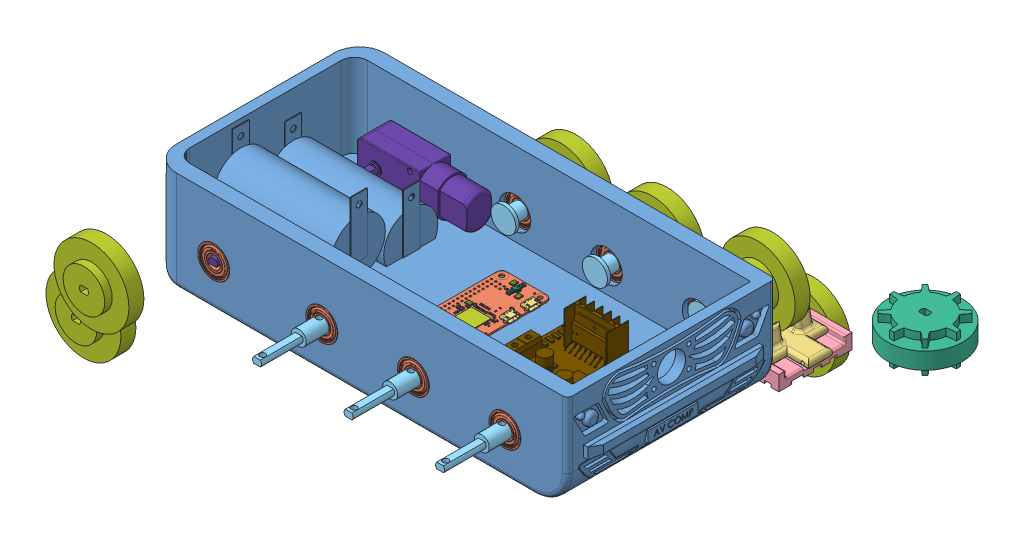
SolidWorks assembly AV_Comp_Mech_1_3_4_TotalAssembly2, configuration Default. Lengths in mm.
Overall size (366.9 156.49 292.26).
131 component instances, 26 part files, 45 mates.
Components (placement in the parent):
- AV_Comp_Mech_1_3_2_4_ChassisV2_Bot-1: AV_Comp_Mech_1_3_2_4_ChassisV2_Bot [Default] at (-27.4355 -20.1708 15.0222) size (256 60 125)
- AV_Comp_Mech_1_3_1_2_Pi_Zero-1: AV_Comp_Mech_1_3_1_2_Pi_Zero [Default] at (-36.7711 -30.2674 -38.0496) x (0 0 -1) z (1 0 0) size (65 4.45 31.23)
  - Raspberry_pizero_PCB-1: Raspberry_pizero_PCB [Default] at (-51.2564 20.0966 13.0542) size (65 1 30)
  - Micro USB_input_female (short)-SMT-1: Micro USB_input_female (short)-SMT [Default] at (-42.3564 22.3216 26.5042) size (7.98 2.94 5.43)
  - Micro USB_input_female (short)-SMT-2: Micro USB_input_female (short)-SMT [Default] at (-29.7564 22.3216 26.5042) size (7.98 2.94 5.43)
  - 0204 - Capacitor-1: 0204 - Capacitor [Default] at (-62.4121 21.3466 11.2398) size (1 0.5 0.6)
  - 0204 - Capacitor-2: 0204 - Capacitor [Default] at (-62.4121 21.3466 12.2528) size (1 0.5 0.6)
  - 0204 - Capacitor-3: 0204 - Capacitor [Default] at (-61.8122 21.3466 13.3136) size (1 0.5 0.6)
  - 0204 - Capacitor-4: 0204 - Capacitor [Default] at (-61.8122 21.3466 14.2646) size (1 0.5 0.6)
  - 0204 - Capacitor-5: 0204 - Capacitor [Default] at (-61.8122 21.3466 15.241) size (1 0.5 0.6)
  - 0204 - Capacitor-6: 0204 - Capacitor [Default] at (-61.8122 21.3466 16.2144) size (1 0.5 0.6)
  - 0204 - Capacitor-7: 0204 - Capacitor [Default] at (-61.8122 21.3466 17.2416) size (1 0.5 0.6)
  - 0204 - Capacitor-8: 0204 - Capacitor [Default] at (-62.5919 21.3466 20.9695) size (1 0.5 0.6)
  - 0204 - Capacitor-9: 0204 - Capacitor [Default] at (-62.5919 21.3466 21.919) size (1 0.5 0.6)
  - 0204 - Capacitor-10: 0204 - Capacitor [Default] at (-60.4584 21.3466 22.3712) x (0 0 1) z (-1 0 0) size (1 0.5 0.6)
  - 0204 - Capacitor-11: 0204 - Capacitor [Default] at (-60.0807 21.3466 22.3712) x (0 0 -1) z (1 0 0) size (1 0.5 0.6)
  - 0204 - Capacitor-12: 0204 - Capacitor [Default] at (-59.0466 21.3466 22.3712) x (0 0 -1) z (1 0 0) size (1 0.5 0.6)
  - 0204 - Capacitor-13: 0204 - Capacitor [Default] at (-52.6496 21.3466 22.316) x (0 0 1) z (-1 0 0) size (1 0.5 0.6)
  - 0204 - Capacitor-14: 0204 - Capacitor [Default] at (-52.25 21.3466 22.316) x (0 0 -1) z (1 0 0) size (1 0.5 0.6)
  - 0204 - Capacitor-15: 0204 - Capacitor [Default] at (-51.2398 21.3466 22.316) x (0 0 -1) z (1 0 0) size (1 0.5 0.6)
  - 0204 - Capacitor-16: 0204 - Capacitor [Default] at (-49.1841 21.3466 22.316) x (0 0 -1) z (1 0 0) size (1 0.5 0.6)
  - 0204 - Capacitor-17: 0204 - Capacitor [Default] at (-48.1448 21.3466 22.316) x (0 0 -1) z (1 0 0) size (1 0.5 0.6)
  - 0204 - Capacitor-18: 0204 - Capacitor [Default] at (-46.475 21.3466 21.113) size (1 0.5 0.6)
  - 0204 - Capacitor-19: 0204 - Capacitor [Default] at (-45.7322 21.3466 20.0663) size (1 0.5 0.6)
  - 0204 - Capacitor-20: 0204 - Capacitor [Default] at (-45.7322 21.3466 19.0675) size (1 0.5 0.6)
  - 0204 - Capacitor-21: 0204 - Capacitor [Default] at (-45.7322 21.3466 18.1249) size (1 0.5 0.6)
  - 0204 - Capacitor-22: 0204 - Capacitor [Default] at (-45.7322 21.3466 17.1095) size (1 0.5 0.6)
  - 0204 - Capacitor-23: 0204 - Capacitor [Default] at (-46.3457 21.3466 16.1412) size (1 0.5 0.6)
  - 0204 - Capacitor-24: 0204 - Capacitor [Default] at (-46.3457 21.3466 15.1229) size (1 0.5 0.6)
  - 0204 - Capacitor-25: 0204 - Capacitor [Default] at (-46.3457 21.3466 14.0197) size (1 0.5 0.6)
  - 0204 - Capacitor-26: 0204 - Capacitor [Default] at (-46.3457 21.3466 12.9589) size (1 0.5 0.6)
  - 0204 - Capacitor-27: 0204 - Capacitor [Default] at (-43.6156 21.3466 13.1418) size (1 0.5 0.6)
  - 0204 - Capacitor-28: 0204 - Capacitor [Default] at (-43.6156 21.3466 10.1424) size (1 0.5 0.6)
  - 0204 - Capacitor-29: 0204 - Capacitor [Default] at (-48.9117 21.3466 7.6917) size (1 0.5 0.6)
  - 0204 - Capacitor-30: 0204 - Capacitor [Default] at (-55.4926 21.3466 7.2526) x (0 0 -1) z (1 0 0) size (1 0.5 0.6)
  - 0204 - Capacitor-31: 0204 - Capacitor [Default] at (-53.7932 21.3466 7.2526) x (0 0 1) z (-1 0 0) size (1 0.5 0.6)
  - 0204 - Capacitor-32: 0204 - Capacitor [Default] at (-59.8477 21.3466 7.2526) x (0 0 1) z (-1 0 0) size (1 0.5 0.6)
  - 0204- Resistor-15: 0204- Resistor [Default] at (-43.6109 21.4522 15.4193) x (-1 0 0) z (0 -1 0) size (0.99 0.51 0.36)
  - 0204- Resistor-14: 0204- Resistor [Default] at (-43.6109 21.4522 14.4127) x (-1 0 0) z (0 -1 0) size (0.99 0.51 0.36)
  - 0204- Resistor-13: 0204- Resistor [Default] at (-43.6109 21.4522 12.4047) x (-1 0 0) z (0 -1 0) size (0.99 0.51 0.36)
  - 0204- Resistor-4: 0204- Resistor [Default] at (-42.6936 21.4522 18.4076) x (-1 0 0) z (0 -1 0) size (0.99 0.51 0.36)
  - 0204- Resistor-5: 0204- Resistor [Default] at (-39.831 21.4522 18.1462) x (0 0 1) z (0 -1 0) size (0.99 0.51 0.36)
  - 0204- Resistor-7: 0204- Resistor [Default] at (-61.8169 21.4522 19.8533) x (-1 0 0) z (0 -1 0) size (0.99 0.51 0.36)
  - 0204- Resistor-8: 0204- Resistor [Default] at (-61.8169 21.4522 18.5178) x (-1 0 0) z (0 -1 0) size (0.99 0.51 0.36)
  - 0204- Resistor-9: 0204- Resistor [Default] at (-79.148 21.4522 17.7279) x (-1 0 0) z (0 -1 0) size (0.99 0.51 0.36)
  - 0204- Resistor-10: 0204- Resistor [Default] at (-56.0985 21.4522 7.2479) x (0 0 -1) z (0 -1 0) size (0.99 0.51 0.36)
  - 0204- Resistor-11: 0204- Resistor [Default] at (-28.0827 21.4522 9.5819) x (-1 0 0) z (0 -1 0) size (0.99 0.51 0.36)
  - 0204- Resistor-12: 0204- Resistor [Default] at (-21.8613 21.4522 20.9026) x (-1 0 0) z (0 -1 0) size (0.99 0.51 0.36)
  - CAP-0306-1: CAP-0306 [Default] at (-45.8903 21.4966 8.7634) size (1.6 0.8 0.9)
  - CAP-0306-2: CAP-0306 [Default] at (-82.0031 21.4966 19.0464) x (0 0 1) z (-1 0 0) size (1.6 0.8 0.9)
  - Raspberry_pizero_BCM2835 with VC4-2: Raspberry_pizero_BCM2835 with VC4 [Default] at (-54.1608 21.5466 15.1238) x (1 0 0) z (0 0 -1) size (12 0.65 12)
  - Crystal 3.4x2.4mm-1: Crystal 3.4x2.4mm [Default] at (-65.3089 21.0966 19.2633) size (3.2 1 2.4)
  - 0204- Resistor-16: 0204- Resistor [Default] at (-68.4329 21.4522 5.4384) x (0 0 1) z (0 -1 0) size (0.99 0.51 0.36)
  - 0204- Resistor-17: 0204- Resistor [Default] at (-69.7255 21.4522 5.4384) x (0 0 1) z (0 -1 0) size (0.99 0.51 0.36)
  - 0204- Resistor-18: 0204- Resistor [Default] at (-65.0626 21.4522 16.5355) x (1 0 0) z (0 -1 0) size (0.99 0.51 0.36)
  - 32,768 Khz Crystal-1: 32,768 Khz Crystal [Default] at (-60.5154 21.1428 26.5473) x (0.999848 -0.017452 0) z (0 0 1) size (3.4 1.03 1.5)
  - 0805- Capacitor-1: 0805- Capacitor [Default] at (-51.9496 21.9966 5.2384) x (1 0 0) z (0 -1 0) size (2 1.25 0.9)
  - 0805- Capacitor-2: 0805- Capacitor [Default] at (-51.9496 21.9966 7.3589) x (1 0 0) z (0 -1 0) size (2 1.25 0.9)
  - 0805- Capacitor-3: 0805- Capacitor [Default] at (-37.009 21.9966 22.5384) x (0 0 -1) z (0 -1 0) size (2 1.25 0.9)
  - 0805- Capacitor-4: 0805- Capacitor [Default] at (-29.8247 21.9966 13.3538) x (0 0 1) z (0 -1 0) size (2 1.25 0.9)
  - 0805- Capacitor-5: 0805- Capacitor [Default] at (-27.9052 21.9966 13.3538) x (0 0 -1) z (0 -1 0) size (2 1.25 0.9)
  - 0805- Capacitor-6: 0805- Capacitor [Default] at (-22.8003 21.9966 13.3538) x (0 0 -1) z (0 -1 0) size (2 1.25 0.9)
  - 0805- Capacitor-7: 0805- Capacitor [Default] at (-20.9924 21.9966 13.3538) x (0 0 -1) z (0 -1 0) size (2 1.25 0.9)
  - 0204- Resistor-19: 0204- Resistor [Default] at (-48.8769 21.4522 23.8207) x (1 0 0) z (0 -1 0) size (0.99 0.51 0.36)
  - 0204- Resistor-20: 0204- Resistor [Default] at (-52.4165 21.4522 24.0419) x (1 0 0) z (0 -1 0) size (0.99 0.51 0.36)
  - 0204 - Capacitor-33: 0204 - Capacitor [Default] at (-47.1199 21.3466 23.926) x (0 0 1) z (-1 0 0) size (1 0.5 0.6)
  - 0204 - Capacitor Brown-34: 0204 - Capacitor Brown [Default] at (-57.5817 21.3466 26.803) size (1 0.5 0.6)
  - 0204 - Capacitor Brown-35: 0204 - Capacitor Brown [Default] at (-64.0312 21.3466 26.8794) size (1 0.5 0.6)
  - 0204 - Capacitor Brown-36: 0204 - Capacitor Brown [Default] at (-46.3457 21.3466 12.214) size (1 0.5 0.6)
  - 0204 - Capacitor Brown-37: 0204 - Capacitor Brown [Default] at (-46.3457 21.3466 11.0963) size (1 0.5 0.6)
  - 0204 - Capacitor Brown-38: 0204 - Capacitor Brown [Default] at (-46.3457 21.3466 10.1566) size (1 0.5 0.6)
  - 0204 - Capacitor Brown-39: 0204 - Capacitor Brown [Default] at (-43.6156 21.3466 11.1151) size (1 0.5 0.6)
  - 0204 - Capacitor Brown-40: 0204 - Capacitor Brown [Default] at (-28.0874 21.3466 10.3236) size (1 0.5 0.6)
  - 0204 - Capacitor Brown-41: 0204 - Capacitor Brown [Default] at (-80.6197 21.3466 20.6997) size (1 0.5 0.6)
  - 0204- Resistor-21: 0204- Resistor [Default] at (-78.9105 21.4522 21.1554) x (1 0 0) z (0 -1 0) size (0.99 0.51 0.36)
  - 6-Pin SOT-1: 6-Pin SOT [Default] at (-79.714 21.0966 19.2138) x (0 0 1) z (0 1 0) size (1.5 1.84 0.95)
  - micro sd molex-1: micro sd molex [Default] at (-74.7768 21.6766 -33.0961) x (0 0 1) z (0 1 0) size (11.95 11.4 1.45)
  - hdmi type C-1: hdmi type C [Default] at (-71.3564 22.9466 28.6542) size (12.9 4.05 7.7)
  - Voltage Regulator 3x3mm 12-Pin-1: Voltage Regulator 3x3mm 12-Pin [Default] at (-23.6842 21.0966 12.6105) x (1 0 0) z (0 1 0) size (3 4.1 1.2)
  - 1210 inductor-1: 1210 inductor [Default] at (-46.4963 21.0916 6.3909) x (0 0 1) z (0 1 0) size (3.26 2.86 0.75)
  - 1210 inductor-2: 1210 inductor [Default] at (-22.7405 21.0916 9.2394) x (1 0 0) z (0 1 0) size (3.26 2.86 0.75)
  - 1210 inductor-3: 1210 inductor [Default] at (-28.2854 21.0916 17.6682) x (1 0 0) z (0 1 0) size (3.26 2.86 0.75)
  - 0204 - Capacitor-34: 0204 - Capacitor [Default] at (-48.9117 21.3466 6.5273) size (1 0.5 0.6)
- AV_Comp_Mech_1_3_1_3_Motors-1: AV_Comp_Mech_1_3_1_3_Motors [Default] at (-114.9355 4.8292 -38.4778) x (0 1 0) z (0 0 1) size (22.6 65.53 37.6)
- AV_Comp_Mech_1_3_1_4_L298N_Motor_Driver-1: AV_Comp_Mech_1_3_1_4_L298N_Motor_Driver [Default] at (33.5292 -10.1708 13.6749) size (50 22 50)
- AV_Comp_Mech_1_3_1_3_Motors-2: AV_Comp_Mech_1_3_1_3_Motors [Default] at (-114.9355 4.8292 49.7222) x (0 1 0) z (0 0 1) size (22.6 65.53 37.6)
- BAT_32700-Lifepo4-Cell-2: BAT_32700-Lifepo4-Cell [Default] at (-75.4355 8.7605 30.2055) x (0 0 -1) z (0 1 0) size (32.5 71.5 44.5)
- 698zz Bearing.step-1: 698zz Bearing.step [Default] at (-49.9355 4.8292 74.7722) x (0.670176 0.742202 0) z (0 0 1) size (19 19 6)
- 698zz Bearing.step-2: 698zz Bearing.step [Default] at (-114.9355 4.8292 74.7722) x (0.988962 -0.148172 0) z (0 0 1) size (19 19 6)
- 698zz Bearing.step-3: 698zz Bearing.step [Default] at (60.0645 4.8292 74.7722) x (-0.091459 -0.995809 0) z (0 0 1) size (19 19 6)
- 698zz Bearing.step-4: 698zz Bearing.step [Default] at (60.0645 4.8292 -44.7278) x (0.992282 0.124006 0) z (0 0 1) size (19 19 6)
- 698zz Bearing.step-5: 698zz Bearing.step [Default] at (-114.9355 4.8292 -44.7278) x (0.998822 0.048528 0) z (0 0 1) size (19 19 6)
- 698zz Bearing.step-6: 698zz Bearing.step [Default] at (5.0645 4.8292 -44.7278) x (0.999749 -0.022386 0) z (0 0 1) size (19 19 6)
- 698zz Bearing.step-7: 698zz Bearing.step [Default] at (5.0645 4.8292 74.7722) x (0.99997 -0.007736 0) z (0 0 1) size (19 19 6)
- 698zz Bearing.step-8: 698zz Bearing.step [Default] at (-49.9355 4.8292 -44.7278) x (0.961867 0.273516 0) z (0 0 1) size (19 19 6)
- BAT_32700-Lifepo4-Cell-3: BAT_32700-Lifepo4-Cell [Default] at (-75.4355 -3.1708 -1.3207) x (0 0 -1) z (0 1 0) size (32.5 71.5 44.5)
- AV_Comp_Mech_1_3_8_CarTop-2: AV_Comp_Mech_1_3_8_CarTop [Default] at (187.4194 -82.0613 67.5222) x (0 0 -1) z (1 0 0) size (115 52.22 250) (hidden)
- AV_Comp_Mech_1_1_9_WholeTrack-1: AV_Comp_Mech_1_1_9_WholeTrack [Default] at (130.5045 -39.0767 -93.7121) size (225.46 19.36 44.35)
  - AV_Comp_Mech_1_1_6_TrackAssembly-1: AV_Comp_Mech_1_1_6_TrackAssembly [Default] at (-66.8469 2.2745 -10.8813) size (35.18 19.36 44)
    - AV_Comp_Mech_1_1_3_TracksV3-1: AV_Comp_Mech_1_1_3_TracksV3 [Default] at (9.2421 14.1316 25.58) size (35.18 14.36 35)
    - AV_Comp_Mech_1_1_5_OuterTrack_TPU_2-1: AV_Comp_Mech_1_1_5_OuterTrack_TPU_2 [Default] at (12.2777 11.1316 25.5805) x (1 0 0) z (0 1 0) size (28.18 44 9)
  - AV_Comp_Mech_1_1_3_TracksV3-1: AV_Comp_Mech_1_1_3_TracksV3 [Default] at (-84.787 16.4061 15.0487) size (35.18 14.36 35)
  - AV_Comp_Mech_1_1_5_OuterTrack_TPU_2-1: AV_Comp_Mech_1_1_5_OuterTrack_TPU_2 [Default] at (-81.7514 13.4061 15.0492) x (1 0 0) z (0 1 0) size (28.18 44 9)
  - AV_Comp_Mech_1_1_5_OuterTrack_TPU_2-3: AV_Comp_Mech_1_1_5_OuterTrack_TPU_2 [Default] at (-136.1157 13.4061 15.0492) x (1 0 0) z (0 1 0) size (28.18 44 9)
  - AV_Comp_Mech_1_1_3_TracksV3-3: AV_Comp_Mech_1_1_3_TracksV3 [Default] at (-139.1513 16.4061 15.0487) size (35.18 14.36 35)
  - AV_Comp_Mech_1_1_6_TrackAssembly-3: AV_Comp_Mech_1_1_6_TrackAssembly [Default] at (-121.2112 2.2745 -10.8813) size (35.18 19.36 44)
    - AV_Comp_Mech_1_1_3_TracksV3-1: AV_Comp_Mech_1_1_3_TracksV3 [Default] at (9.2421 14.1316 25.58) size (35.18 14.36 35)
    - AV_Comp_Mech_1_1_5_OuterTrack_TPU_2-1: AV_Comp_Mech_1_1_5_OuterTrack_TPU_2 [Default] at (12.2777 11.1316 25.5805) x (1 0 0) z (0 1 0) size (28.18 44 9)
  - AV_Comp_Mech_1_1_5_OuterTrack_TPU_2-4: AV_Comp_Mech_1_1_5_OuterTrack_TPU_2 [Default] at (-190.48 13.4061 15.0492) x (1 0 0) z (0 1 0) size (28.18 44 9)
  - AV_Comp_Mech_1_1_5_OuterTrack_TPU_2-5: AV_Comp_Mech_1_1_5_OuterTrack_TPU_2 [Default] at (-244.8444 13.4061 15.0492) x (1 0 0) z (0 1 0) size (28.18 44 9)
  - AV_Comp_Mech_1_1_3_TracksV3-4: AV_Comp_Mech_1_1_3_TracksV3 [Default] at (-247.8799 16.4061 15.0487) size (35.18 14.36 35)
  - AV_Comp_Mech_1_1_6_TrackAssembly-4: AV_Comp_Mech_1_1_6_TrackAssembly [Default] at (-229.9399 2.2745 -10.8813) size (35.18 19.36 44)
    - AV_Comp_Mech_1_1_3_TracksV3-1: AV_Comp_Mech_1_1_3_TracksV3 [Default] at (9.2421 14.1316 25.58) size (35.18 14.36 35)
    - AV_Comp_Mech_1_1_5_OuterTrack_TPU_2-1: AV_Comp_Mech_1_1_5_OuterTrack_TPU_2 [Default] at (12.2777 11.1316 25.5805) x (1 0 0) z (0 1 0) size (28.18 44 9)
  - AV_Comp_Mech_1_1_3_TracksV3-5: AV_Comp_Mech_1_1_3_TracksV3 [Default] at (-193.5156 16.4061 15.0487) size (35.18 14.36 35)
  - AV_Comp_Mech_1_1_6_TrackAssembly-5: AV_Comp_Mech_1_1_6_TrackAssembly [Default] at (-175.5755 2.2745 -10.8813) size (35.18 19.36 44)
    - AV_Comp_Mech_1_1_3_TracksV3-1: AV_Comp_Mech_1_1_3_TracksV3 [Default] at (9.2421 14.1316 25.58) size (35.18 14.36 35)
    - AV_Comp_Mech_1_1_5_OuterTrack_TPU_2-1: AV_Comp_Mech_1_1_5_OuterTrack_TPU_2 [Default] at (12.2777 11.1316 25.5805) x (1 0 0) z (0 1 0) size (28.18 44 9)
- AV_Comp_Mech_1_1_10_DriverAxle-1: AV_Comp_Mech_1_1_10_DriverAxle [Default] at (60.0645 4.8292 -39.8028) x (0.050541 0.998722 0) z (-0.998722 0.050541 0) size (15 55 15)
- AV_Comp_Mech_1_1_7_DriverWheel-1: AV_Comp_Mech_1_1_7_DriverWheel [Default] at (110.2825 -28.7562 -124.6796) size (45 19 45)
- AV_Comp_Mech_1_1_8_GroundWheel-1: AV_Comp_Mech_1_1_8_GroundWheel [Default] at (60.0621 4.8293 -87.8028) x (0.050541 0.998722 0) z (0 0 1) size (45 45 18)
- AV_Comp_Mech_1_1_10_DriverAxle-2: AV_Comp_Mech_1_1_10_DriverAxle [Default] at (5.0645 4.8292 -31.4778) x (-0.895903 0.444249 0) z (-0.444249 -0.895903 0) size (15 55 15)
- AV_Comp_Mech_1_1_10_DriverAxle-3: AV_Comp_Mech_1_1_10_DriverAxle [Default] at (-49.9355 4.8292 -31.4778) x (0.247012 0.969012 0) z (-0.969012 0.247012 0) size (15 55 15)
- AV_Comp_Mech_1_1_10_DriverAxle-4: AV_Comp_Mech_1_1_10_DriverAxle [Default] at (-49.9355 4.8292 61.5222) x (1 0 0) z (0 -1 0) size (15 55 15)
- AV_Comp_Mech_1_1_10_DriverAxle-5: AV_Comp_Mech_1_1_10_DriverAxle [Default] at (60.0645 4.8292 61.5222) x (1 0 0) z (0 -1 0) size (15 55 15)
- AV_Comp_Mech_1_1_10_DriverAxle-6: AV_Comp_Mech_1_1_10_DriverAxle [Default] at (5.0645 4.8292 61.5222) x (1 0 0) z (0 -1 0) size (15 55 15)
- AV_Comp_Mech_1_1_8_GroundWheel-2: AV_Comp_Mech_1_1_8_GroundWheel [Default] at (5.0661 4.8297 -79.4778) x (-0.895603 0.444854 0) z (0 0 1) size (45 45 18)
- AV_Comp_Mech_1_1_8_GroundWheel-3: AV_Comp_Mech_1_1_8_GroundWheel [Default] at (-3.5616 -94.1567 -175.7363) size (45 45 18)
- AV_Comp_Mech_1_1_8_GroundWheel-4: AV_Comp_Mech_1_1_8_GroundWheel [Default] at (-169.89 -25.9473 82.5802) size (45 45 18)
- AV_Comp_Mech_1_1_8_GroundWheel-5: AV_Comp_Mech_1_1_8_GroundWheel [Default] at (-49.9355 4.8292 -79.4778) x (-0.247012 -0.969012 0) z (0 0 1) size (45 45 18)
- AV_Comp_Mech_1_1_8_GroundWheel-6: AV_Comp_Mech_1_1_8_GroundWheel [Default] at (-211.6148 -80.2344 45.6639) size (45 45 18)
Mates (geometry in assembly coordinates):
- Parallel2: parallel anti-aligned: plane of AV_Comp_Mech_1_3_2_4_ChassisV2_Bot-1 through (-27.4355 -10.1708 15.0222) normal (0 1 0); plane of AV_Comp_Mech_1_3_1_3_Motors-2 through (-126.1355 -6.4208 68.5222) normal (0 -1 0)
- Concentric37: concentric anti-aligned: circle of AV_Comp_Mech_1_3_2_4_ChassisV2_Bot-1; cylinder of AV_Comp_Mech_1_3_1_3_Motors-2 through (-114.9355 4.8292 69.0222) axis (0 0 -1) radius 3.6
- Concentric39: concentric aligned: cylinder of AV_Comp_Mech_1_3_2_4_ChassisV2_Bot-1 through (-114.9355 4.8292 -74.3478) axis (0 0 1) radius 9.5; cylinder of 698zz Bearing.step-2 through (-114.9355 4.8292 1074.7722) axis (0 0 1) radius 9.5
- Coincident30: coincident aligned: circle of AV_Comp_Mech_1_3_2_4_ChassisV2_Bot-1; circle of 698zz Bearing.step-2
- Concentric40: concentric aligned: cylinder of AV_Comp_Mech_1_3_2_4_ChassisV2_Bot-1 through (-49.9355 4.8292 -74.3478) axis (0 0 1) radius 9.5; cylinder of 698zz Bearing.step-1 through (-49.9355 4.8292 1074.7722) axis (0 0 1) radius 9.5
- Coincident31: coincident aligned: circle of AV_Comp_Mech_1_3_2_4_ChassisV2_Bot-1; circle of 698zz Bearing.step-1
- Concentric41: concentric aligned: cylinder of AV_Comp_Mech_1_3_2_4_ChassisV2_Bot-1 through (5.0645 4.8292 -74.3478) axis (0 0 1) radius 9.5; cylinder of 698zz Bearing.step-7 through (5.0645 4.8292 1074.7722) axis (0 0 1) radius 9.5
- Coincident32: coincident aligned: circle of AV_Comp_Mech_1_3_2_4_ChassisV2_Bot-1; circle of 698zz Bearing.step-7
- Concentric42: concentric aligned: cylinder of AV_Comp_Mech_1_3_2_4_ChassisV2_Bot-1 through (60.0645 4.8292 -74.3478) axis (0 0 1) radius 9.5; cylinder of 698zz Bearing.step-3 through (60.0645 4.8292 1074.7722) axis (0 0 1) radius 9.5
- Coincident33: coincident aligned: circle of AV_Comp_Mech_1_3_2_4_ChassisV2_Bot-1; circle of 698zz Bearing.step-3
- Concentric70: concentric aligned: cylinder of AV_Comp_Mech_1_3_2_4_ChassisV2_Bot-1 through (60.0645 4.8292 -74.3478) axis (0 0 1) radius 9.5; cylinder of 698zz Bearing.step-4 through (60.0645 4.8292 955.2722) axis (0 0 1) radius 9.5
- Coincident45: coincident anti-aligned: circle of AV_Comp_Mech_1_3_2_4_ChassisV2_Bot-1; circle of 698zz Bearing.step-4
- Concentric73: concentric aligned: cylinder of AV_Comp_Mech_1_3_2_4_ChassisV2_Bot-1 through (5.0645 4.8292 -74.3478) axis (0 0 1) radius 9.5; cylinder of 698zz Bearing.step-6 through (5.0645 4.8292 955.2722) axis (0 0 1) radius 9.5
- Coincident47: coincident anti-aligned: circle of AV_Comp_Mech_1_3_2_4_ChassisV2_Bot-1; circle of 698zz Bearing.step-6
- Concentric76: concentric aligned: cylinder of AV_Comp_Mech_1_3_2_4_ChassisV2_Bot-1 through (-49.9355 4.8292 -74.3478) axis (0 0 1) radius 9.5; cylinder of 698zz Bearing.step-8 through (-49.9355 4.8292 955.2722) axis (0 0 1) radius 9.5
- Coincident49: coincident anti-aligned: circle of AV_Comp_Mech_1_3_2_4_ChassisV2_Bot-1; circle of 698zz Bearing.step-8
- Concentric79: concentric aligned: cylinder of AV_Comp_Mech_1_3_2_4_ChassisV2_Bot-1 through (-114.9355 4.8292 -74.3478) axis (0 0 1) radius 9.5; cylinder of 698zz Bearing.step-5 through (-114.9355 4.8292 955.2722) axis (0 0 1) radius 9.5
- Coincident51: coincident anti-aligned: circle of AV_Comp_Mech_1_3_2_4_ChassisV2_Bot-1; circle of 698zz Bearing.step-5
- Parallel8: parallel anti-aligned: plane of AV_Comp_Mech_1_3_2_4_ChassisV2_Bot-1 through (-27.4355 -10.1708 15.0222) normal (0 1 0); plane of AV_Comp_Mech_1_3_1_3_Motors-1 through (-126.1355 -6.4208 -19.6778) normal (0 -1 0)
- Concentric80: concentric aligned: circle of AV_Comp_Mech_1_3_2_4_ChassisV2_Bot-1; circle of AV_Comp_Mech_1_3_1_3_Motors-1
- Coincident53: coincident anti-aligned: plane of AV_Comp_Mech_1_3_2_4_ChassisV2_Bot-1 through (91.5645 -10.1708 -38.4778) normal (0 0 1); plane of AV_Comp_Mech_1_3_1_3_Motors-1 through (-114.9355 4.8292 -38.4778) normal (0 0 -1)
- Coincident58: coincident anti-aligned: plane of AV_Comp_Mech_1_3_2_4_ChassisV2_Bot-1 through (-146.4355 -10.1708 68.5222) normal (1 0 0); plane of BAT_32700-Lifepo4-Cell-2 through (-146.4355 8.7605 30.2055) normal (-1 0 0)
- Coincident59: coincident anti-aligned: plane of AV_Comp_Mech_1_3_2_4_ChassisV2_Bot-1 through (-146.4355 -10.1708 68.5222) normal (1 0 0); plane of BAT_32700-Lifepo4-Cell-3 through (-146.4355 -3.1708 -1.3207) normal (-1 0 0)
- Coincident60: coincident anti-aligned: plane of AV_Comp_Mech_1_3_2_4_ChassisV2_Bot-1 through (-27.4355 -10.1708 15.0222) normal (0 1 0); plane of BAT_32700-Lifepo4-Cell-3 through (-74.9355 -10.1708 -1.3207) normal (0 -1 0)
- Coincident61: coincident anti-aligned: plane of AV_Comp_Mech_1_3_2_4_ChassisV2_Bot-1 through (91.5645 -10.1708 68.5222) normal (0 0 -1); plane of AV_Comp_Mech_1_3_1_3_Motors-2 through (-114.9355 4.8292 68.5222) normal (0 0 1)
- Coincident62: coincident anti-aligned: plane of AV_Comp_Mech_1_3_2_4_ChassisV2_Bot-1 through (-27.4355 -10.1708 15.0222) normal (0 1 0); plane of AV_Comp_Mech_1_3_1_2_Pi_Zero-1/Raspberry_pizero_PCB-1 through (-35.7168 -10.1708 42.7067) normal (0 -1 0)
- Parallel10: parallel anti-aligned: plane of AV_Comp_Mech_1_3_2_4_ChassisV2_Bot-1 through (91.5645 -10.1708 -38.4778) normal (0 0 1); plane of AV_Comp_Mech_1_3_1_2_Pi_Zero-1/Raspberry_pizero_PCB-1 through (-11.7168 -9.1708 -19.2933) normal (0 0 -1)
- Coincident63: coincident anti-aligned: plane of AV_Comp_Mech_1_3_2_4_ChassisV2_Bot-1 through (-27.4355 -10.1708 15.0222) normal (0 1 0); plane of AV_Comp_Mech_1_3_1_4_L298N_Motor_Driver-1 through (33.5292 -10.1708 13.6749) normal (0 -1 0)
- Coincident67: coincident aligned: line of AV_Comp_Mech_1_3_2_4_ChassisV2_Bot-1 through (-152.4355 39.8292 -32.4778) axis (0 0 1); line of AV_Comp_Mech_1_3_8_CarTop-2 through (-152.4355 39.8292 -32.4778) axis (0 0 1)
- Coincident68: coincident aligned: line of AV_Comp_Mech_1_3_2_4_ChassisV2_Bot-1 through (94.5645 39.8292 -47.4778) axis (-1 0 0); line of AV_Comp_Mech_1_3_8_CarTop-2 through (97.5645 39.8292 -47.4778) axis (-1 0 0)
- Concentric85: concentric aligned: cylinder of 698zz Bearing.step-4 through (60.0645 4.8292 955.2722) axis (0 0 1) radius 4; cylinder of AV_Comp_Mech_1_1_10_DriverAxle-1 through (60.0645 4.8292 -94.8028) axis (0 0 1) radius 4.5
- Coincident70: coincident anti-aligned: plane of AV_Comp_Mech_1_1_10_DriverAxle-1 through (61.7725 2.7402 -69.8028) normal (0.998722 -0.050541 0); plane of AV_Comp_Mech_1_1_8_GroundWheel-1 through (61.7725 2.7402 -87.8028) normal (-0.998722 0.050541 0)
- Coincident71: coincident: plane of AV_Comp_Mech_1_1_10_DriverAxle-1 through (60.0645 4.8292 -69.8028) normal (0 0 -1); line of AV_Comp_Mech_1_1_8_GroundWheel-1 through (61.7725 2.7402 -69.8028) axis (0.050541 0.998722 0)
- Tangent7: tangent aligned: cylinder of AV_Comp_Mech_1_1_10_DriverAxle-1 through (60.0645 4.8292 -69.8028) axis (0 0 -1) radius 2.6983; cylinder of AV_Comp_Mech_1_1_8_GroundWheel-1 through (60.0621 4.8293 -87.8028) axis (0 0 1) radius 2.7
- Tangent8: tangent anti-aligned: plane of AV_Comp_Mech_1_1_9_WholeTrack-1/AV_Comp_Mech_1_1_3_TracksV3-1 through (45.7176 -17.6707 -78.6634) normal (0 1 0); cylinder of AV_Comp_Mech_1_1_8_GroundWheel-1 through (60.0621 4.8293 -83.3028) axis (0 0 1) radius 22.5
- Tangent9: tangent: curve of AV_Comp_Mech_1_1_9_WholeTrack-1/AV_Comp_Mech_1_1_3_TracksV3-1; plane of AV_Comp_Mech_1_1_8_GroundWheel-1 through (60.0621 4.8293 -83.3028) normal (0 0 -1)
- Parallel15: parallel aligned: plane of AV_Comp_Mech_1_3_2_4_ChassisV2_Bot-1 through (-27.4355 -20.1708 15.0222) normal (0 -1 0); plane of AV_Comp_Mech_1_1_9_WholeTrack-1/AV_Comp_Mech_1_1_5_OuterTrack_TPU_2-5 through (-114.3399 -27.6707 -78.6629) normal (0 -1 0)
- Parallel16: parallel aligned: plane of AV_Comp_Mech_1_3_2_4_ChassisV2_Bot-1 through (-152.4355 39.8292 -47.4778) normal (0 0 -1); plane of AV_Comp_Mech_1_1_9_WholeTrack-1/AV_Comp_Mech_1_1_6_TrackAssembly-5/AV_Comp_Mech_1_1_5_OuterTrack_TPU_2-1 through (-46.8834 -27.6707 -101.0129) normal (0 0 -1)
- Coincident76: coincident anti-aligned: plane of AV_Comp_Mech_1_1_10_DriverAxle-2 through (5.0645 4.8292 -61.4778) normal (0 0 -1); plane of AV_Comp_Mech_1_1_8_GroundWheel-2 through (5.0879 4.8736 -61.4778) normal (0 0 1)
- Coincident80: coincident anti-aligned: line of AV_Comp_Mech_1_1_10_DriverAxle-2 through (2.468 4.0949 -61.4778) axis (0 0 -1); line of AV_Comp_Mech_1_1_8_GroundWheel-2 through (2.468 4.0949 -79.4778) axis (0 0 1)
- Tangent11: tangent aligned: cylinder of AV_Comp_Mech_1_1_10_DriverAxle-2 through (5.0645 4.8292 -61.4778) axis (0 0 -1) radius 2.6983; cylinder of AV_Comp_Mech_1_1_8_GroundWheel-2 through (5.0661 4.8297 -79.4778) axis (0 0 1) radius 2.7
- Concentric92: concentric anti-aligned: cylinder of AV_Comp_Mech_1_1_10_DriverAxle-3 through (-49.9355 4.8292 -61.4778) axis (0 0 -1) radius 2.6983; cylinder of AV_Comp_Mech_1_1_8_GroundWheel-5 through (-49.9355 4.8292 -79.4778) axis (0 0 1) radius 2.7
- Parallel20: parallel anti-aligned: plane of AV_Comp_Mech_1_1_10_DriverAxle-3 through (-52.1847 3.3386 -61.4778) normal (-0.969012 0.247012 0); plane of AV_Comp_Mech_1_1_8_GroundWheel-5 through (-51.1991 7.2153 -79.4778) normal (0.969012 -0.247012 0)
- Coincident83: coincident anti-aligned: plane of AV_Comp_Mech_1_1_10_DriverAxle-3 through (-49.9355 4.8292 -61.4778) normal (0 0 -1); plane of AV_Comp_Mech_1_1_8_GroundWheel-5 through (-49.983 4.8413 -61.4778) normal (0 0 1)
- Coincident84: coincident anti-aligned: plane of 698zz Bearing.step-4 through (59.2282 11.5217 -41.8028) normal (0 0 1); plane of AV_Comp_Mech_1_1_10_DriverAxle-1 through (60.0645 4.8292 -41.8028) normal (0 0 -1)
